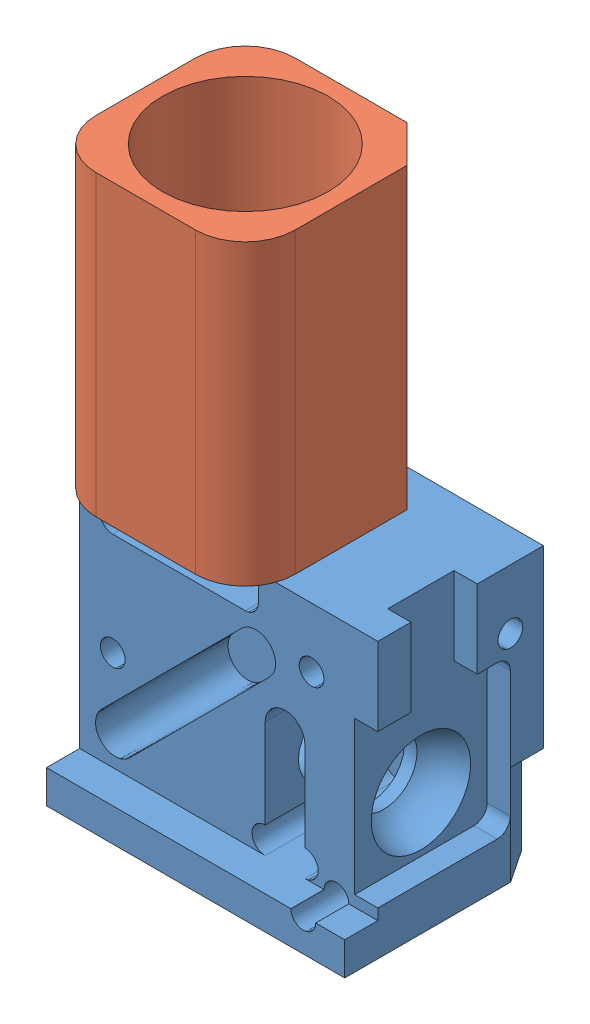
SolidWorks assembly Assem1, configuration Default. Lengths in mm.
Overall size (9 17.3 6).
2 component instances, 2 part files, 4 mates.
Components (placement in the parent):
- MS_MainBodyv3.3_BOTTOM-1: MS_MainBodyv3.3_BOTTOM [Default] at (2.1322 0.4771 7.4333) size (9 8.8 6)
- MS_MainBodyv3.3_TOP-1: MS_MainBodyv3.3_TOP [Default] at (0.6322 13.2771 7.4333) size (6 9 6)
Mates (geometry in assembly coordinates):
- Concentric1: concentric: cylinder of MS_MainBodyv3.3_BOTTOM-1 through (0.6322 17.7772 7.4333) axis (0 -1 0) radius 1.5; cylinder of MS_MainBodyv3.3_TOP-1 through (0.6322 18.2771 7.4333) axis (0 -1 0) radius 2.5
- Parallel2: parallel: plane of MS_MainBodyv3.3_BOTTOM-1 through (-1.6178 9.2771 5.1833) normal (0 0 1); plane of MS_MainBodyv3.3_TOP-1 through (-1.6178 10.2771 5.1833) normal (0 0 -1)
- Parallel3: parallel: plane of MS_MainBodyv3.3_BOTTOM-1 through (-1.6178 9.2771 4.9333) normal (-1 0 0); plane of MS_MainBodyv3.3_TOP-1 through (-1.3678 10.2771 5.1833) normal (-1 0 0)
- Coincident7: coincident: plane of MS_MainBodyv3.3_BOTTOM-1 through (2.1322 8.7771 7.4333) normal (0 1 0); plane of MS_MainBodyv3.3_TOP-1 through (0.6322 8.7771 7.4333) normal (0 -1 0)
